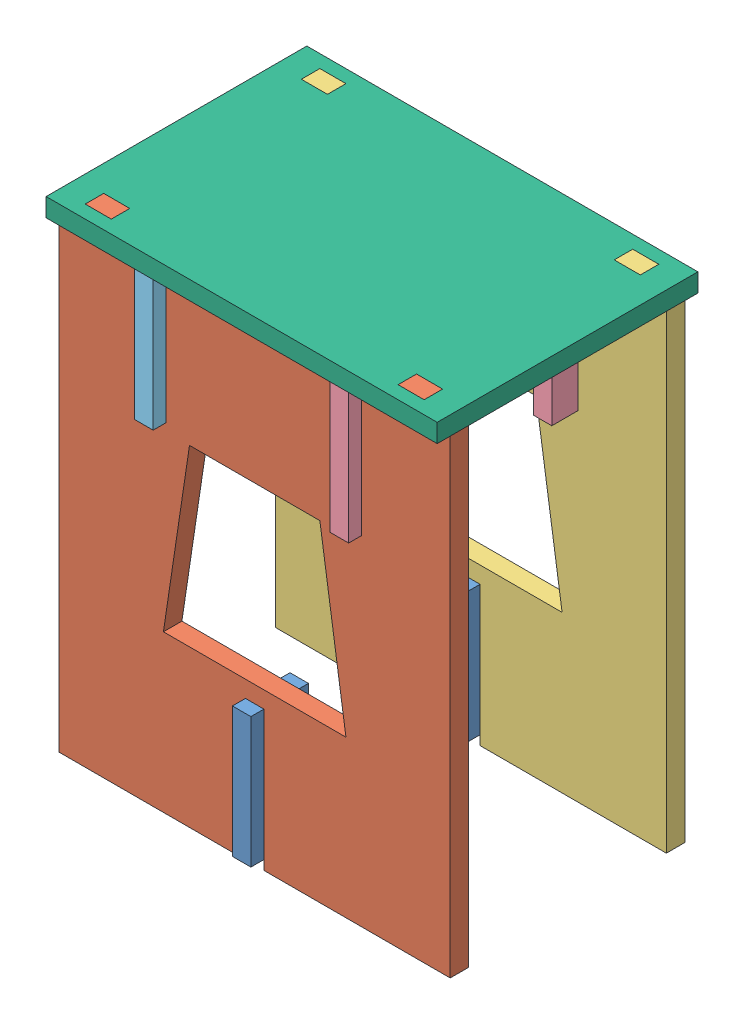
SolidWorks assembly Assem1, configuration Default. Lengths in mm.
Overall size (381 475.2 254).
6 component instances, 6 part files, 15 mates.
Components (placement in the parent):
- Part1-1: Part1 [Default] at (57.7309 -1.1364 384.4688) size (18 127 254)
- Part2-1: Part2 [Default] at (-123.7691 -10.2804 353.7688) size (381 475.2 18)
- Part3-1: Part3 [Default] at (-123.7691 -10.2804 143.1688) size (381 475.2 18)
- Part4-1: Part4 [Default] at (152.9809 446.9196 130.4688) x (1 0 0) z (0 0 -1) size (18 127 254)
- Part5-1: Part5 [Default] at (-37.5191 446.9196 130.4688) x (1 0 0) z (0 0 -1) size (18 127 254)
- Part6-1: Part6 [Default] at (-123.7691 446.9196 384.4688) size (381 18 254)
Mates (geometry in assembly coordinates):
- Width3: width aligned: plane of Part2-1 through (-123.7691 -10.2804 353.7688) normal (0 0 -1); plane of Part2-1 through (-123.7691 -10.2804 371.7688) normal (0 0 1); plane of Part1-1 through (57.7309 125.8636 371.7688) normal (0 0 -1); plane of Part1-1 through (57.7309 125.8636 353.7688) normal (0 0 1)
- Coincident3: coincident anti-aligned: plane of Part1-1 through (75.7309 49.6636 384.4688) normal (0 1 0); plane of Part2-1 through (-123.7691 49.6636 353.7688) normal (0 -1 0)
- Width4: width anti-aligned: plane of Part1-1 through (57.7309 -1.1364 384.4688) normal (-1 0 0); plane of Part1-1 through (75.7309 -1.1364 384.4688) normal (1 0 0); plane of Part2-1 through (57.7309 49.6636 371.7688) normal (1 0 0); plane of Part2-1 through (75.7309 49.6636 371.7688) normal (-1 0 0)
- Width5: width anti-aligned: plane of Part3-1 through (-123.7691 -10.2804 143.1688) normal (0 0 -1); plane of Part3-1 through (-123.7691 -10.2804 161.1688) normal (0 0 1); plane of Part1-1 through (57.7309 125.8636 143.1688) normal (0 0 1); plane of Part1-1 through (57.7309 125.8636 161.1688) normal (0 0 -1)
- Width6: width anti-aligned: plane of Part1-1 through (57.7309 -1.1364 384.4688) normal (-1 0 0); plane of Part1-1 through (75.7309 -1.1364 384.4688) normal (1 0 0); plane of Part3-1 through (57.7309 49.6636 161.1688) normal (1 0 0); plane of Part3-1 through (75.7309 49.6636 161.1688) normal (-1 0 0)
- Coincident4: coincident anti-aligned: plane of Part1-1 through (75.7309 49.6636 384.4688) normal (0 1 0); plane of Part3-1 through (-123.7691 49.6636 143.1688) normal (0 -1 0)
- Width11: width aligned: plane of Part4-1 through (152.9809 319.9196 371.7688) normal (0 0 -1); plane of Part4-1 through (152.9809 319.9196 353.7688) normal (0 0 1); plane of Part2-1 through (-123.7691 -10.2804 353.7688) normal (0 0 -1); plane of Part2-1 through (-123.7691 -10.2804 371.7688) normal (0 0 1)
- Width12: width aligned: plane of Part2-1 through (170.9809 396.1196 353.7688) normal (-1 0 0); plane of Part2-1 through (152.9809 396.1196 353.7688) normal (1 0 0); plane of Part4-1 through (152.9809 446.9196 130.4688) normal (-1 0 0); plane of Part4-1 through (170.9809 446.9196 130.4688) normal (1 0 0)
- Coincident6: coincident anti-aligned: plane of Part2-1 through (-123.7691 396.1196 353.7688) normal (0 1 0); plane of Part4-1 through (170.9809 396.1196 130.4688) normal (0 -1 0)
- Width13: width aligned: plane of Part5-1 through (-19.5191 446.9196 130.4688) normal (1 0 0); plane of Part5-1 through (-37.5191 446.9196 130.4688) normal (-1 0 0); plane of Part2-1 through (-37.5191 396.1196 353.7688) normal (1 0 0); plane of Part2-1 through (-19.5191 396.1196 353.7688) normal (-1 0 0)
- Width14: width aligned: plane of Part2-1 through (-123.7691 -10.2804 353.7688) normal (0 0 -1); plane of Part2-1 through (-123.7691 -10.2804 371.7688) normal (0 0 1); plane of Part5-1 through (-37.5191 319.9196 371.7688) normal (0 0 -1); plane of Part5-1 through (-37.5191 319.9196 353.7688) normal (0 0 1)
- Coincident7: coincident anti-aligned: plane of Part2-1 through (-123.7691 396.1196 353.7688) normal (0 1 0); plane of Part5-1 through (-19.5191 396.1196 130.4688) normal (0 -1 0)
- Symmetric1: symmetric anti-aligned: plane of Part2-1 through (-123.7691 446.9196 371.7688) normal (0 1 0); plane of Part3-1 through (-123.7691 446.9196 161.1688) normal (0 1 0); plane of Part6-1 through (8.642 446.9196 384.4688) normal (0 -1 0)
- Coincident9: coincident anti-aligned: plane of Part3-1 through (-123.7691 -10.2804 161.1688) normal (0 0 1); plane of Part6-1 through (34.042 446.9196 161.1688) normal (0 0 -1)
- Coincident10: coincident anti-aligned: plane of Part3-1 through (-72.9691 464.9196 161.1688) normal (1 0 0); plane of Part6-1 through (-72.9691 446.9196 143.1688) normal (-1 0 0)
